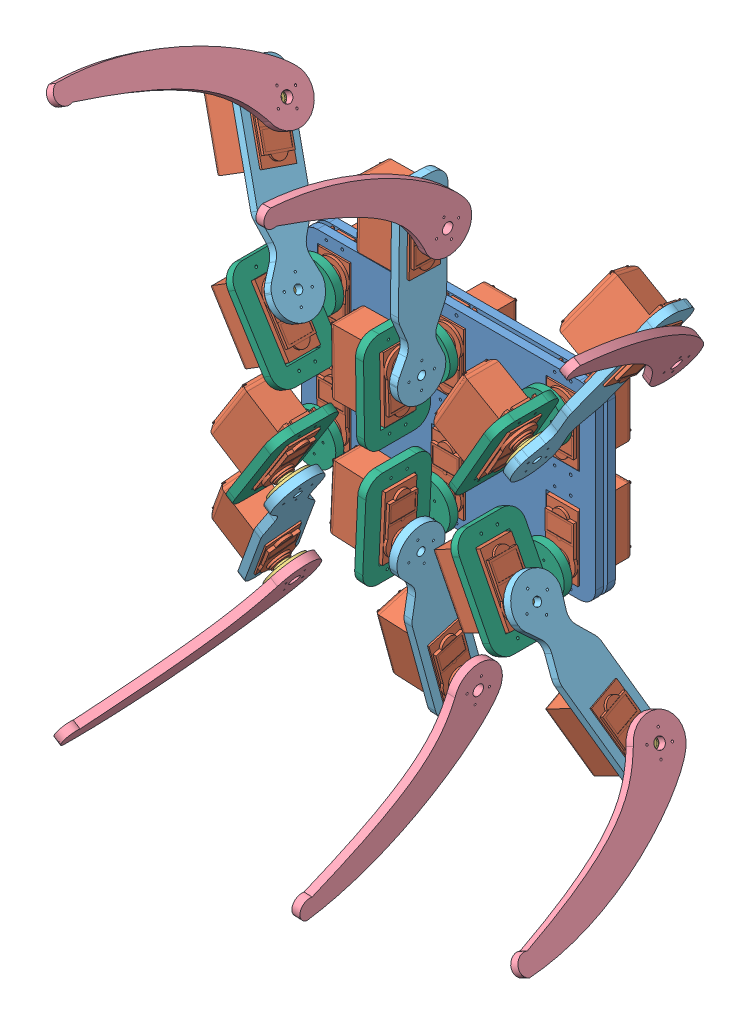
SolidWorks assembly Try1, configuration Default. Lengths in mm.
Overall size (334.07 453.36 181.15).
62 component instances, 6 part files, 21 mates.
Components (placement in the parent):
- base-1: base [Default] at (181.5723 -115.0659 22.8405) size (183 118 5)
- left_leg-1: left_leg [Default] at (181.4795 55.1175 31.3619) x (0 1 0) z (0 0 1) size (179.7 159.86 138.37) (flexible)
  - Standard Servo-1: Standard Servo [Default] at (0.6119 -1.2439 -1.43) x (0.786888 -0.452256 -0.419848) z (-0.36401 0.209211 -0.907594) size (53.74 42.63 19.57)
  - Horn-1: Horn [Default] at (-11.9936 -44.8638 -4.6726) x (-0.860885 0.494785 0.118593) z (0.102821 -0.059095 0.992943) size (24 5 24)
  - leg_3-1: leg_3 [Default] at (-11.9936 -44.8638 -4.6726) x (-0.853975 0.490813 -0.172711) z (-0.498301 -0.867004 0) size (110.29 105.51 5)
  - leg_2-1: leg_2 [Default] at (-75.07 2.6213 15.3274) x (-0.786888 0.452256 0.419848) z (0.498301 0.867004 0) size (120 30 5)
  - Standard Servo-2: Standard Servo [Default] at (-58.7771 49.889 29.4081) x (0.867004 -0.498301 0) z (0 0 -1) size (53.74 42.63 19.57)
  - Horn-2: Horn [Default] at (-71.0681 6.0882 31.0024) x (-0.855116 0.491469 0.165026) z (0.143079 -0.082233 0.986289) size (24 5 24)
  - leg_1-1: leg_1 [Default] at (-54.676 -6.5178 6.2174) x (0.867004 -0.498301 0) z (0 0 1) size (61.5 30 46)
  - Standard Servo-3: Standard Servo [Default] at (-81.3467 18.098 -37.8826) x (1 0 0) z (0 -1 0) size (53.74 42.63 19.57)
  - Horn-3: Horn [Default] at (-70.177 19.6922 6.2174) x (1 0 0) z (0 -1 0) size (24 5 24)
- left_leg-2: left_leg [Default] at (39.4795 55.1175 31.3619) x (0 1 0) z (0 0 1) size (213.72 104.3 164.37) (flexible)
  - Standard Servo-1: Standard Servo [Default] at (-14.6981 74.4267 9.1344) x (0.81618 0.508449 -0.274462) z (-0.232957 -0.145123 -0.961598) size (53.74 42.63 19.57)
  - Horn-1: Horn [Default] at (18.1078 42.9063 7.6018) x (-0.842785 -0.525023 0.118593) z (0.100659 0.062707 0.992943) size (24 5 24)
  - leg_3-1: leg_3 [Default] at (18.1078 42.9063 7.6018) x (-0.78872 -0.491342 -0.369464) z (0.528754 -0.848775 0) size (110.29 105.51 5)
  - leg_2-1: leg_2 [Default] at (-55.3676 8.6078 15.2465) x (-0.81618 -0.508449 0.274462) z (-0.528754 0.848775 0) size (120 30 5)
  - Standard Servo-2: Standard Servo [Default] at (-91.4063 44.0052 29.4081) x (0.848775 0.528754 0) z (0 0 -1) size (53.74 42.63 19.57)
  - Horn-2: Horn [Default] at (-58.6077 12.4802 31.0024) x (-0.837138 -0.521504 0.165026) z (0.14007 0.087258 0.986289) size (24 5 24)
  - leg_1-1: leg_1 [Default] at (-39.7532 20.9726 6.2174) x (0.848775 0.528754 0) z (0 0 1) size (61.5 30 46)
  - Standard Servo-3: Standard Servo [Default] at (-81.3467 18.098 -37.8826) x (1 0 0) z (0 -1 0) size (53.74 42.63 19.57)
  - Horn-3: Horn [Default] at (-70.177 19.6922 6.2174) x (1 0 0) z (0 -1 0) size (24 5 24)
- left_leg-3: left_leg [Default] at (110.4795 55.1175 31.3619) x (0 1 0) z (0 0 1) size (222.91 63.48 181.15) (flexible)
  - Standard Servo-1: Standard Servo [Default] at (8.8215 37.9808 27.061) x (0.999468 0.014728 -0.029083) z (-0.02908 -0.000429 -0.999577) size (53.74 42.63 19.57)
  - Horn-1: Horn [Default] at (20.6814 -5.9493 28.3297) x (-0.992835 -0.01463 0.118593) z (0.118581 0.001747 0.992943) size (24 5 24)
  - leg_3-1: leg_3 [Default] at (20.6814 -5.9493 28.3297) x (-0.951721 -0.014024 -0.306644) z (0.014734 -0.999891 0) size (110.29 105.51 5)
  - leg_2-1: leg_2 [Default] at (-59.3549 2.6111 15.9053) x (-0.999468 -0.014728 0.029083) z (-0.014734 0.999891 0) size (120 30 5)
  - Standard Servo-2: Standard Servo [Default] at (-75.8092 51.474 29.4081) x (0.999891 0.014734 0) z (0 0 -1) size (53.74 42.63 19.57)
  - Horn-2: Horn [Default] at (-63.991 7.5433 31.0024) x (-0.986182 -0.014532 0.165026) z (0.165009 0.002432 0.986289) size (24 5 24)
  - leg_1-1: leg_1 [Default] at (-43.4589 5.0843 6.2174) x (0.999891 0.014734 0) z (0 0 1) size (61.5 30 46)
  - Standard Servo-3: Standard Servo [Default] at (-81.3467 18.098 -37.8826) x (1 0 0) z (0 -1 0) size (53.74 42.63 19.57)
  - Horn-3: Horn [Default] at (-70.177 19.6922 6.2174) x (1 0 0) z (0 -1 0) size (24 5 24)
- right_leg-1: right_leg [Default] at (180.782 -7.3937 31.3619) x (-0.008727 0.999962 0) z (0 0 1) size (188.75 151.3 157.56) (flexible)
  - Standard Servo-1: Standard Servo [Default] at (-165.3584 1.5156 9.2814) x (-0.849174 -0.420459 -0.319559) z (-0.286377 -0.141796 0.947566) size (53.74 42.63 19.57)
  - Horn-1: Horn [Default] at (-154.8186 -42.4756 4.2013) x (-0.864613 -0.428104 -0.263005) z (-0.235695 -0.116702 0.964795) size (24 5 24)
  - leg_3-1: leg_3 [Default] at (-152.6 -46.9564 4.2013) x (0.850565 0.421148 -0.314919) z (-0.443725 0.896163 0) size (110.29 105.51 5)
  - leg_2-1: leg_2 [Default] at (-89.4986 6.3134 15.2309) x (0.849174 0.420459 0.319559) z (0.443725 -0.896163 0) size (120 30 5)
  - Standard Servo-2: Standard Servo [Default] at (-99.0948 50.7718 32.5966) x (-0.896163 -0.443725 0) z (0 0 1) size (53.74 42.63 19.57)
  - Horn-2: Horn [Default] at (-89.5364 6.2947 31.0024) x (-0.891461 -0.441397 0.102306) z (0.091683 0.045396 0.994753) size (24 5 24)
  - leg_1-1: leg_1 [Default] at (-119.9136 21.4603 6.2174) x (-0.896163 -0.443725 0) z (0 0 1) size (61.5 30 46)
  - Standard Servo-3: Standard Servo [Default] at (-78.3263 21.2733 -37.8826) x (-0.999962 0.008727 0) z (0.008727 0.999962 0) size (53.74 42.63 19.57)
  - Horn-3: Horn [Default] at (-89.5094 19.7766 6.2174) x (0.993551 -0.113383 0) z (-0.113383 -0.993551 0) size (24 5 24)
- right_leg-2: right_leg [Default] at (38.782 -7.3937 31.3619) x (-0.008727 0.999962 0) z (0 0 1) size (211.05 106.28 161.18) (flexible)
  - Standard Servo-1: Standard Servo [Default] at (-143.7854 75.3532 8.2077) x (-0.792119 0.510824 -0.334076) z (-0.280758 0.181056 0.942546) size (53.74 42.63 19.57)
  - Horn-1: Horn [Default] at (-176.086 43.7085 2.9735) x (-0.810816 0.522882 -0.263005) z (-0.22103 0.142538 0.964795) size (24 5 24)
  - leg_3-1: leg_3 [Default] at (-178.7958 39.5065 2.9735) x (0.772386 -0.498099 -0.394104) z (0.541962 0.840403 0) size (110.29 105.51 5)
  - leg_2-1: leg_2 [Default] at (-100.8597 12.734 15.2334) x (0.792119 -0.510824 0.334076) z (-0.541962 -0.840403 0) size (120 30 5)
  - Standard Servo-2: Standard Servo [Default] at (-67.8112 43.8964 32.5966) x (-0.840403 0.541962 0) z (0 0 1) size (53.74 42.63 19.57)
  - Horn-2: Horn [Default] at (-101.0987 12.8881 31.0024) x (-0.835993 0.539118 0.102306) z (0.085979 -0.055446 0.994753) size (24 5 24)
  - leg_1-1: leg_1 [Default] at (-103.6507 46.7446 6.2174) x (-0.840403 0.541962 0) z (0 0 1) size (61.5 30 46)
  - Standard Servo-3: Standard Servo [Default] at (-78.3263 21.2733 -37.8826) x (-0.999962 0.008727 0) z (0.008727 0.999962 0) size (53.74 42.63 19.57)
  - Horn-3: Horn [Default] at (-89.5094 19.7766 6.2174) x (0.993551 -0.113383 0) z (-0.113383 -0.993551 0) size (24 5 24)
- right_leg-3: right_leg [Default] at (109.782 -7.3937 31.3619) x (-0.008727 0.999962 0) z (0 0 1) size (221.31 62.15 153.15) (flexible)
  - Standard Servo-1: Standard Servo [Default] at (-165.0719 41.2907 11.189) x (-0.954411 0.053002 -0.293751) z (-0.2933 0.016288 0.955882) size (53.74 42.63 19.57)
  - Horn-1: Horn [Default] at (-177.71 -2.1754 6.384) x (-0.96331 0.053496 -0.263005) z (-0.2626 0.014583 0.964795) size (24 5 24)
  - leg_3-1: leg_3 [Default] at (-177.9872 -7.1677 6.384) x (0.973764 -0.054076 -0.221041) z (0.055448 0.998462 0) size (110.29 105.51 5)
  - leg_2-1: leg_2 [Default] at (-96.5607 8.0796 15.2356) x (0.954411 -0.053002 0.293751) z (-0.055448 -0.998462 0) size (120 30 5)
  - Standard Servo-2: Standard Servo [Default] at (-82.5781 51.471 32.5966) x (-0.998462 0.055448 0) z (0 0 1) size (53.74 42.63 19.57)
  - Horn-2: Horn [Default] at (-96.1758 8.0582 31.0024) x (-0.993223 0.055157 0.102306) z (0.102149 -0.005673 0.994753) size (24 5 24)
  - leg_1-1: leg_1 [Default] at (-115.137 36.2229 6.2174) x (-0.998462 0.055448 0) z (0 0 1) size (61.5 30 46)
  - Standard Servo-3: Standard Servo [Default] at (-78.3263 21.2733 -37.8826) x (-0.999962 0.008727 0) z (0.008727 0.999962 0) size (53.74 42.63 19.57)
  - Horn-3: Horn [Default] at (-89.5094 19.7766 6.2174) x (0.993551 -0.113383 0) z (-0.113383 -0.993551 0) size (24 5 24)
- base-2: base [Default] at (181.5723 -115.0659 15.5492) size (183 118 5)
Mates (geometry in assembly coordinates):
- Coincident1: coincident: plane of assembly; plane of assembly; plane of base-1 through (171.5723 -4.5659 27.8405) normal (-1 0 0); plane of left_leg-1/Standard Servo-3 through (171.5723 -44.8859 28.8492) normal (1 0 0)
- Coincident2: coincident: plane of base-1 through (100.5723 -4.5659 27.8405) normal (-1 0 0); plane of left_leg-3/Standard Servo-3 through (100.5723 -44.8859 28.8492) normal (1 0 0)
- Coincident3: coincident: plane of base-1 through (29.5723 -4.5659 27.8405) normal (-1 0 0); plane of left_leg-2/Standard Servo-3 through (29.5723 -44.8859 28.8492) normal (1 0 0)
- Coincident4: coincident: plane of base-1 through (171.5723 -66.0659 27.8405) normal (-1 0 0); plane of right_leg-1/Standard Servo-3 through (171.5723 -67.2459 28.8492) normal (1 0 0)
- Coincident5: coincident: plane of base-1 through (100.5723 -66.0659 27.8405) normal (-1 0 0); plane of right_leg-3/Standard Servo-3 through (100.5723 -67.2459 28.8492) normal (1 0 0)
- Coincident6: coincident: plane of base-1 through (29.5723 -66.0659 27.8405) normal (-1 0 0); plane of right_leg-2/Standard Servo-3 through (29.5723 -67.2459 28.8492) normal (1 0 0)
- Coincident16: coincident: plane of base-1 through (150.5723 -107.5659 27.8405) normal (0 1 0); plane of right_leg-1/Standard Servo-3 through (171.5723 -107.5659 28.8492) normal (0 -1 0)
- Coincident17: coincident: plane of base-1 through (79.5723 -107.5659 27.8405) normal (0 1 0); plane of right_leg-3/Standard Servo-3 through (100.5723 -107.5659 28.8492) normal (0 -1 0)
- Coincident18: coincident: plane of base-1 through (8.5723 -107.5659 27.8405) normal (0 1 0); plane of right_leg-2/Standard Servo-3 through (29.5723 -107.5659 28.8492) normal (0 -1 0)
- Coincident19: coincident: plane of assembly; plane of assembly; plane of base-1 through (150.5723 -4.5659 27.8405) normal (0 -1 0); plane of left_leg-1/Standard Servo-3 through (152.0023 -4.5659 28.8492) normal (0 1 0)
- Coincident20: coincident: plane of base-1 through (79.5723 -4.5659 27.8405) normal (0 -1 0); plane of left_leg-3/Standard Servo-3 through (81.0023 -4.5659 28.8492) normal (0 1 0)
- Coincident21: coincident: plane of base-1 through (8.5723 -4.5659 27.8405) normal (0 -1 0); plane of left_leg-2/Standard Servo-3 through (10.0023 -4.5659 28.8492) normal (0 1 0)
- Coincident22: coincident: plane of base-1 through (181.5723 -115.0659 22.8405) normal (0 0 -1); plane of right_leg-1/Standard Servo-3 through (171.5723 -60.5359 22.8405) normal (0 0 1)
- Coincident23: coincident: plane of base-1 through (181.5723 -115.0659 22.8405) normal (0 0 -1); plane of right_leg-3/Standard Servo-3 through (100.5723 -60.5359 22.8405) normal (0 0 1)
- Coincident24: coincident: plane of base-1 through (181.5723 -115.0659 22.8405) normal (0 0 -1); plane of right_leg-2/Standard Servo-3 through (29.5723 -60.5359 22.8405) normal (0 0 1)
- Coincident25: coincident: plane of assembly; plane of assembly; plane of base-1 through (181.5723 -115.0659 22.8405) normal (0 0 -1); plane of left_leg-1/Standard Servo-3 through (152.0023 -51.5959 22.8405) normal (0 0 1)
- Coincident26: coincident: plane of base-1 through (181.5723 -115.0659 22.8405) normal (0 0 -1); plane of left_leg-3/Standard Servo-3 through (81.0023 -51.5959 22.8405) normal (0 0 1)
- Coincident27: coincident: plane of base-1 through (181.5723 -115.0659 22.8405) normal (0 0 -1); plane of left_leg-2/Standard Servo-3 through (10.0023 -51.5959 22.8405) normal (0 0 1)
- Coincident28: coincident: plane of assembly; plane of assembly; plane of base-1 through (181.5723 -115.0659 27.8405) normal (0 -1 0); plane of base-2 through (181.5723 -115.0659 20.5492) normal (0 -1 0)
- Coincident29: coincident: plane of assembly; plane of assembly; plane of base-1 through (181.5723 -115.0659 27.8405) normal (1 0 0); plane of base-2 through (181.5723 -115.0659 20.5492) normal (1 0 0)
- Coincident30: coincident: plane of right_leg-1/Standard Servo-3 through (171.5723 -114.2759 20.5492) normal (0 0 -1); plane of base-2 through (181.5723 -115.0659 20.5492) normal (0 0 1)
